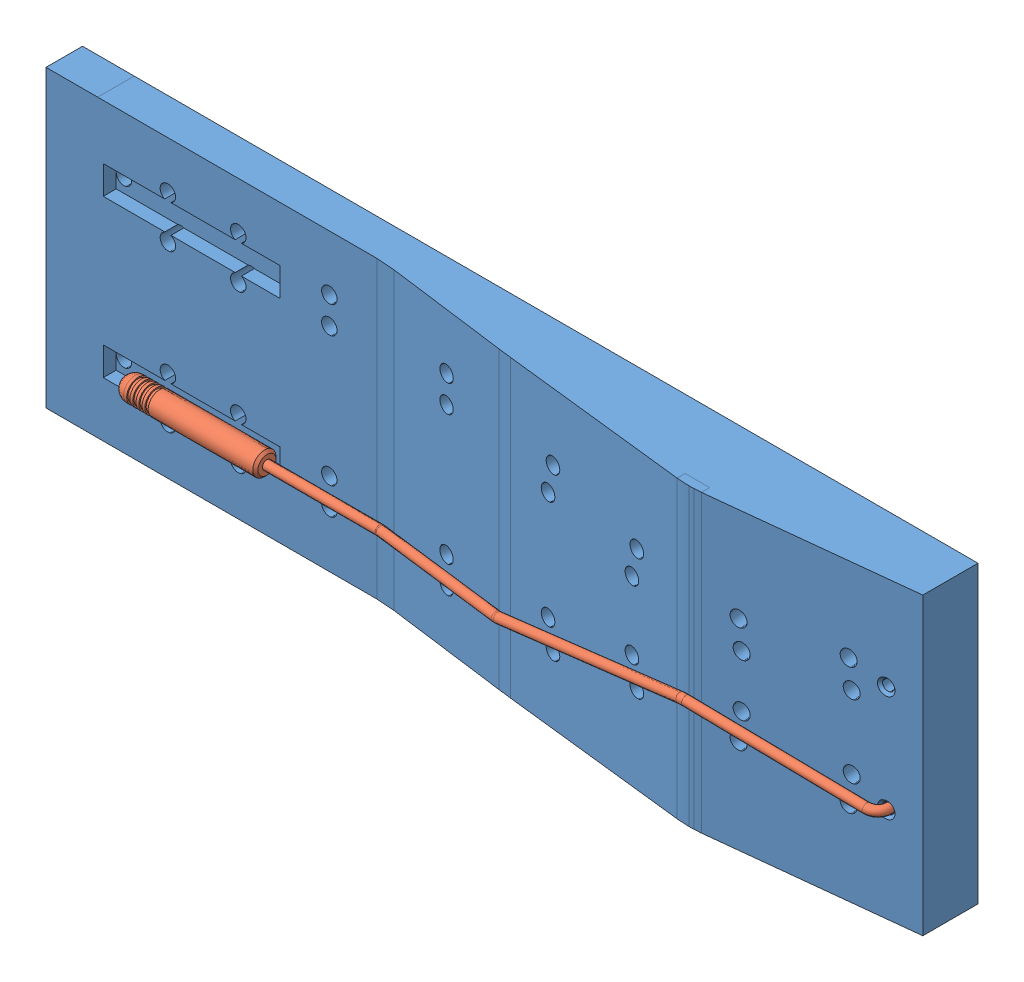
SolidWorks assembly Long Fixture, configuration Default. Lengths in mm.
Overall size (346.58 122.17 65.42).
2 component instances, 2 part files, 0 mates.
Components (placement in the parent):
- Saina_Long Fixture-1: Saina_Long Fixture [Default] at (-207.1081 36.3274 24.5601) size (346.58 114.52 30.32)
- Part1-1: Part1 [Default] at (102.6052 -2.8789 36.8396) x (-0.991142 0.102382 0.084594) z (0.102382 0.994736 -0.00435) size (298.48 40.11 46.29)
